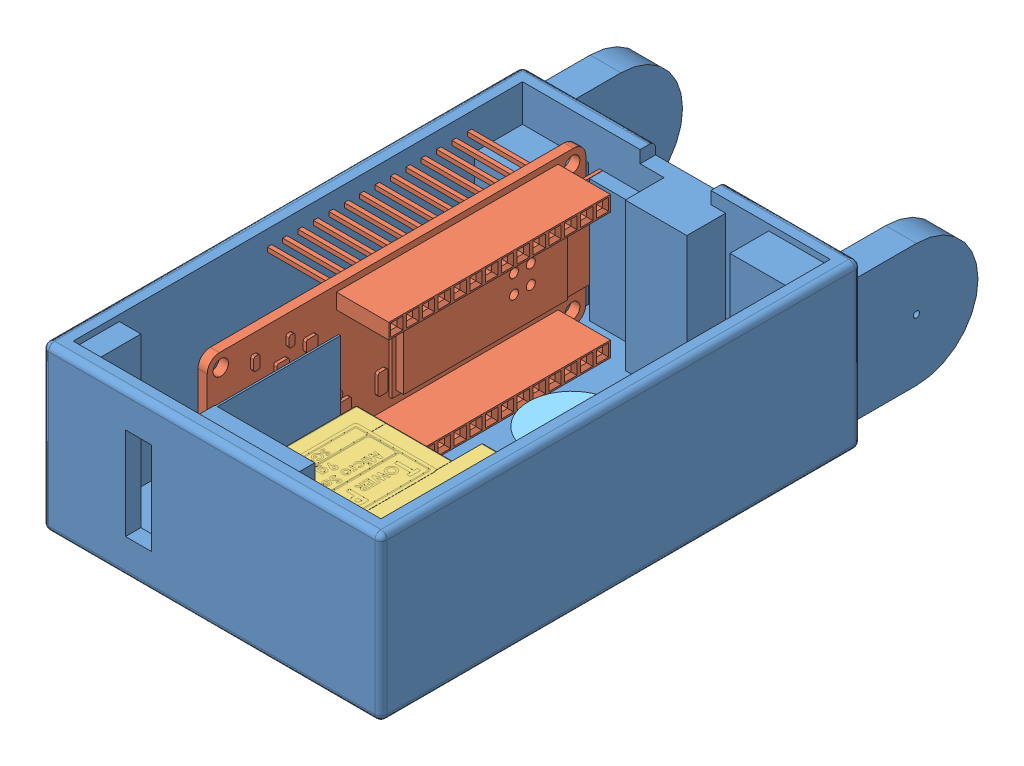
SolidWorks assembly Box Assembly without a cover, configuration Predeterminado. Lengths in mm.
Overall size (55 26.5 98).
5 component instances, 5 part files, 10 mates.
Components (placement in the parent):
- modified servo housing-1: modified servo housing [Predeterminado] at (-2.2195 0.18 147) size (55 26.5 98)
- ArduinoMKR1000 usedforassembly-1: ArduinoMKR1000 usedforassembly [Default] at (-16.2195 -0.07 104.472) x (0 -1 0) z (0 0 1) size (25 21 64.15)
- SG90 BODYusedforassembly-1: SG90 BODYusedforassembly [Default] at (13.7742 0.0284 117.0553) x (0 0 -1) z (0 -1 0) size (32.36 29.6 12.65)
- SG90 ARMusedforassemblye-1: SG90 ARMusedforassemblye [Default] at (20.6703 -6.2708 123.3545) x (0 0.162862 0.986649) z (0 0.986649 -0.162862) size (19.74 4.23 7.24)
- Inner guide of the box-1: Inner guide of the box [Predeterminado] at (9.2805 -7.57 100) x (0.588079 0 -0.808804) z (0.808804 0 0.588079) size (14 10 14)
Mates (geometry in assembly coordinates):
- Coincidente25: coincident anti-aligned: plane of SG90 BODY-1 through (18.0541 -12.57 117.0553) normal (1 0 0); plane of SG90 ARM-1 through (18.0541 -6.2708 123.3545) normal (-1 0 0)
- Concéntrica3: concentric aligned: cylinder of SG90 BODY-1 through (56.943 -6.2708 123.3545) axis (-1 0 0) radius 2.286; cylinder of SG90 ARM-1 through (20.3909 -6.2708 123.3545) axis (-1 0 0) radius 2.286
- Coincidente26: coincident anti-aligned: plane of modified servo housing-1 through (-2.2195 -12.57 147) normal (0 1 0); plane of SG90 BODY-1 through (13.7742 -12.57 117.0553) normal (0 -1 0)
- Coincidente27: coincident anti-aligned: plane of modified servo housing-1 through (22.7805 -12.57 144.5) normal (0 0 -1); plane of SG90 BODY-1 through (7.0305 -12.57 144.5) normal (0 0 1)
- Coincidente35: coincident anti-aligned: plane of modified servo housing-1 through (7.0305 10.93 144.5) normal (1 0 0); plane of SG90 BODY-1 through (7.0305 -12.57 112.1404) normal (-1 0 0)
- Coincidente36: coincident anti-aligned: plane of modified servo housing-1 through (22.7805 -12.57 71.5) normal (0 0 1); plane of Arduino MKR1000 Part-1 through (-14.2195 -0.07 71.5) normal (0 0 -1)
- Coincidente37: coincident anti-aligned: plane of modified servo housing-1 through (-2.2195 -12.57 147) normal (0 1 0); plane of Arduino MKR1000 Part-1 through (-14.7195 -12.57 135.222) normal (0 -1 0)
- Coincidente39: coincident anti-aligned: plane of modified servo housing-1 through (-27.2195 -12.57 144.5) normal (1 0 0); plane of Arduino MKR1000 Part-1 through (-27.2195 -0.07 104.472) normal (-1 0 0)
- Coincidente40: coincident anti-aligned: plane of modified servo housing-1 through (9.2805 -10.57 100) normal (0 1 0); plane of posibleCilindrodeguiadentrodelacaja-1 through (9.2805 -10.57 100) normal (0 -1 0)
- Concéntrica4: concentric aligned: cylinder of modified servo housing-1 through (9.2805 -10.57 100) axis (0 -1 0) radius 1.5; cylinder of posibleCilindrodeguiadentrodelacaja-1 through (9.2805 -10.57 100) axis (0 -1 0) radius 1.5
